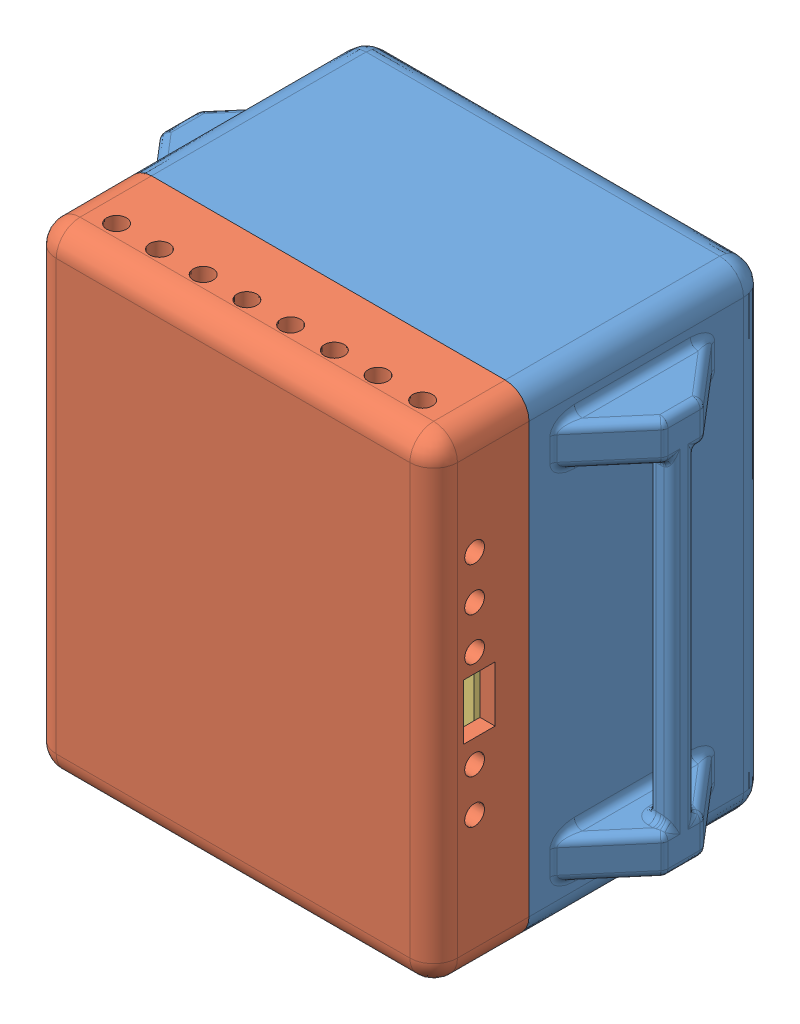
SolidWorks assembly CASE_BATTERIE_FUORI, configuration Default. Lengths in mm.
Overall size (50.5 60 40.1).
77 component instances, 44 part files, 13 mates.
Components (placement in the parent):
- Sotto-1: Sotto [Default] at (-26.2964 -32.0057 39.05) size (63.55 60 35)
- Sensiron-1: Sensiron [Default] at (-24.3964 -30.1057 49.95) x (1 0 0) z (0 -1 0) size (40 12 40) (hidden)
- BatterieSLDPRT-1: BatterieSLDPRT [Default] at (-24.3964 -25.9057 53.95) size (44 52 11) (hidden)
- AssiemePCB-1: AssiemePCB [Default] at (-5.3863 -1.9261 26.258) size (59.61 41 16.91) (hidden)
  - PCB(2).step-1: PCB(2).step [Default] at (-23.3102 -47.5911 44.908) size (45.7 41 1.78)
    - PCB Component.step-1: PCB Component.step [Default] at origin size (45.7 41 1.78)
      - Board.step-1: Board.step [Default] at origin size (41 41 1.58)
      - 2996TR.step-1: 2996TR.step [Default] at (40.14 34.65 0) x (1 0 0) z (0 0 -1) size (13.21 12.07 0.1)
      - 2996TR.step-2: 2996TR.step [Default] at (21.69 34.65 0) x (1 0 0) z (0 0 -1) size (13.21 12.07 0.1)
      - 2996TR.step-3: 2996TR.step [Default] at (20.86 59.95 0) x (-1 0 0) z (0 0 -1) size (13.21 12.07 0.1)
      - 2996TR.step-4: 2996TR.step [Default] at (39.96 59.63 0) x (-1 0 0) z (0 0 -1) size (13.21 12.07 0.1)
      - SCD41-D-R2.step-1: SCD41-D-R2.step [Default] at (41.35 59.4 1.584) size (12.1 12.1 0.1)
      - BSS138.step-1: BSS138.step [Default] at (39.94 37.09 1.584) size (3 3.14 0.1)
      - BSS138.step-2: BSS138.step [Default] at (47.24 35.01 1.584) x (0 1 0) z (0 0 1) size (3 3.14 0.1)
      - BSS138.step-3: BSS138.step [Default] at (26.44 55.43 1.584) x (0 1 0) z (0 0 1) size (3 3.14 0.1)
      - BSS138.step-4: BSS138.step [Default] at (32.54 55.75 1.584) x (0 1 0) z (0 0 1) size (3 3.14 0.1)
      - TSV912IDT.step-1: TSV912IDT.step [Default] at (28.16 33.68 1.584) x (0 -1 0) z (0 0 1) size (6.3 5.13 0.1)
      - SGP30.step-1: SGP30.step [Default] at (42.4 33.66 1.584) x (-1 0 0) z (0 0 1) size (2.88 2.88 0.1)
      - MICS-6814.step-1: MICS-6814.step [Default] at (20.41 33.71 1.584) x (0 1 0) z (0 0 1) size (6.34 7 0.1)
      - 317030213.step-1: 317030213.step [Default] at (18.77 47.25 1.584) x (0 1 0) z (0 0 1) size (11.45 16 0.1)
      - BME280.step-1: BME280.step [Default] at (43.18 50.09 1.584) size (2.95 2.77 0.1)
      - EG1213.step-1: EG1213.step [Default] at (48.7 47.1 1.584) x (0 1 0) z (0 0 1) size (11.2 9 0.1) (hidden)
      - MC78LC50NTRGTSOT23-5_ONS.step-1: MC78LC50NTRGTSOT23-5_ONS.step [Default] at (29.4 47.4 0) x (-1 0 0) z (0 0 -1) size (2.79 3.33 0.1)
      - MIC5219-3.3YMMMSOP-8LD-PL-1_MCH.step-1: MIC5219-3.3YMMMSOP-8LD-PL-1_MCH.step [Default] at (36 47.2 0) x (-1 0 0) z (0 0 -1) size (4.9 3.53 0.1)
      - S-1318D18-M5T1U4.step-1: S-1318D18-M5T1U4.step [Default] at (43.3 46.3 0) x (1 0 0) z (0 0 -1) size (4.2 3.6 0.1)
      - MMBT3904-215.step-1: MMBT3904-215.step [Default] at (18.6 39.2 1.584) x (0 -1 0) z (0 0 1) size (3.16 3.12 0.1)
      - ECS-.327-9-16-TR.step-1: ECS-.327-9-16-TR.step [Default] at (29.5 44.1 1.584) x (0 -1 0) z (0 0 1) size (1.6 1 0.1)
      - BG306-04-A-1-0400-X-X_REVD.step-1: BG306-04-A-1-0400-X-X_REVD.step [Default] at (18 61.2 1.584) x (0 -1 0) z (0 0 1) size (10.66 4 0.1)
      - STMICROELECTRONICS_LIS3DHSTMICROELECTRONICS_LIS3DH_0_0.step-1: STMICROELECTRONICS_LIS3DHSTMICROELECTRONICS_LIS3DH_0_0.step [Default] at (33.8 50.2 1.584) x (-1 0 0) z (0 0 1) size (3.43 3.15 0.1)
      - S5B-ZR-SM4A-TF_(LF)_(SN)CONN_S5B-ZR-SM4A-TF_JST.step-1: S5B-ZR-SM4A-TF_(LF)_(SN)CONN_S5B-ZR-SM4A-TF_JST.step [Default] at (24.1 59.8 1.584) size (12.9 6.25 0.1)
      - LTST-C170KRKT.step-1: LTST-C170KRKT.step [Default] at (48.7 55.3 1.584) x (0 -1 0) z (0 0 1) size (2 1.25 0.1)
      - MCS0402MC1002FE000.step-1: MCS0402MC1002FE000.step [Default] at (39.8 33.2 1.584) x (0 -1 0) z (0 0 1) size (1.06 0.56 0.1)
      - MCS0402MC1002FE000.step-2: MCS0402MC1002FE000.step [Default] at (39.8 39.9 1.584) size (1.06 0.56 0.1)
      - MCS0402MC1002FE000.step-3: MCS0402MC1002FE000.step [Default] at (44.8 34.1 1.584) x (0 -1 0) z (0 0 1) size (1.06 0.56 0.1)
      - MCS0402MC1002FE000.step-4: MCS0402MC1002FE000.step [Default] at (46.1 38.1 1.584) x (-1 0 0) z (0 0 1) size (1.06 0.56 0.1)
      - MCS0402MC1002FE000.step-5: MCS0402MC1002FE000.step [Default] at (29.2 57.1 1.584) x (0 -1 0) z (0 0 1) size (1.06 0.56 0.1)
      - MCS0402MC1002FE000.step-6: MCS0402MC1002FE000.step [Default] at (33 53.1 1.584) size (1.06 0.56 0.1)
      - MCS0402MC1002FE000.step-7: MCS0402MC1002FE000.step [Default] at (23.8 56.9 1.584) x (0 1 0) z (0 0 1) size (1.06 0.56 0.1)
      - MCS0402MC1002FE000.step-8: MCS0402MC1002FE000.step [Default] at (29.9 54.4 1.584) x (0 1 0) z (0 0 1) size (1.06 0.56 0.1)
      - ERJPA2F1300X.step-1: ERJPA2F1300X.step [Default] at (16.1 38.2 1.584) x (0 1 0) z (0 0 1) size (1 0.5 0.1)
      - ERJPA2J821X.step-1: ERJPA2J821X.step [Default] at (22.5 38.1 1.584) x (0 1 0) z (0 0 1) size (1 0.5 0.1)
      - ERA2AEB331X.step-1: ERA2AEB331X.step [Default] at (48.7 60.4 1.584) x (0 -1 0) z (0 0 1) size (1 0.5 0.1)
      - ERJPA2F5101X.step-1: ERJPA2F5101X.step [Default] at (21.4 40.3 1.584) x (0 -1 0) z (0 0 1) size (1 0.5 0.1)
      - ERJ-2GEJ106X.step-1: ERJ-2GEJ106X.step [Default] at (34.5 36.6 1.584) size (1.06 0.56 0.1)
      - ERJ-2GEJ106X.step-2: ERJ-2GEJ106X.step [Default] at (34.4 31.6 1.584) x (-1 0 0) z (0 0 1) size (1.06 0.56 0.1)
      - ERJ-2GEJ106X.step-3: ERJ-2GEJ106X.step [Default] at (32.5 45.7 0) x (0 1 0) z (0 0 -1) size (1.06 0.56 0.1)
      - ERJ-2GEJ106X.step-4: ERJ-2GEJ106X.step [Default] at (33.4 43 0) x (0 -1 0) z (0 0 -1) size (1.06 0.56 0.1)
      - ERJ-2GEJ515X.step-1: ERJ-2GEJ515X.step [Default] at (32.2 36.5 1.584) x (0 -1 0) z (0 0 1) size (1.06 0.56 0.1)
      - ERJ-2GEJ515X.step-2: ERJ-2GEJ515X.step [Default] at (32.1 32.5 1.584) x (0 -1 0) z (0 0 1) size (1.06 0.56 0.1)
      - C0402C104K9RACAUTO.step-1: C0402C104K9RACAUTO.step [Default] at (32 47.8 0) x (0 1 0) z (0 0 -1) size (1.06 0.96 0.1)
      - C0402C104K9RACAUTO.step-2: C0402C104K9RACAUTO.step [Default] at (29.4 45.1 0) x (-1 0 0) z (0 0 -1) size (1.06 0.96 0.1)
      - C0402C104K9RACAUTO.step-3: C0402C104K9RACAUTO.step [Default] at (43.2 31.1 1.584) size (1.06 0.96 0.1)
      - CL05A225MQ5NNNC.step-1: CL05A225MQ5NNNC.step [Default] at (39.7 44.8 0) x (1 0 0) z (0 0 -1) size (1.06 0.96 0.1)
      - CL05B471KB5NNNCCAP_CL05_SAM.step-1: CL05B471KB5NNNCCAP_CL05_SAM.step [Default] at (36.1 44.8 0) x (1 0 0) z (0 0 -1) size (1 0.5 0.1)
      - JMK105BJ105KV-F.step-1: JMK105BJ105KV-F.step [Default] at (40.6 46.7 0) x (0 1 0) z (0 0 -1) size (1.06 0.56 0.1)
      - JMK105BJ105KV-F.step-2: JMK105BJ105KV-F.step [Default] at (43.6 43.7 0) x (1 0 0) z (0 0 -1) size (1.06 0.56 0.1)
      - CL05B103KO5NNNC.step-1: CL05B103KO5NNNC.step [Default] at (34.4 38.5 1.584) x (-1 0 0) z (0 0 1) size (1.06 0.96 0.1)
      - CL05B103KO5NNNC.step-2: CL05B103KO5NNNC.step [Default] at (34.4 33.7 1.584) size (1.06 0.96 0.1)
      - CL05B103KO5NNNC.step-3: CL05B103KO5NNNC.step [Default] at (32.1 43 0) x (0 -1 0) z (0 0 -1) size (1.06 0.96 0.1)
      - CL05A106MP5NUNC.step-1: CL05A106MP5NUNC.step [Default] at (26.6 40.4 1.584) x (-1 0 0) z (0 0 1) size (1.06 0.96 0.1)
      - 04025A120FAT2A.step-1: 04025A120FAT2A.step [Default] at (31.6 43.3 1.584) x (-1 0 0) z (0 0 1) size (1.1 0.6 0.1)
      - 04025A120FAT2A.step-2: 04025A120FAT2A.step [Default] at (31.6 44.8 1.584) x (-1 0 0) z (0 0 1) size (1.1 0.6 0.1)
  - Micro.step-1: Micro.step [Default] at (-4.5401 -1.0595 46.492) x (0 1 0) z (1 0 0) size (10 2.2 16)
  - SCD41.step-1: SCD41.step [Default] at (18.0381 11.8123 47.292) size (10.1 10.1 6.31)
  - Programmatore.stp-1: Programmatore.stp [Default] at (-5.3139 13.6094 46.492) x (0 1 0) z (0 0 1) size (10.66 5 5.4)
    - Body.stp-1: Body.stp [Default] at (0 0 0.1) size (10.66 2.54 5.3)
    - Pins.stp-1: Pins.stp [Default] at origin size (8.44 5 0.1)
  - Battery_holder.step-2: Battery_holder.step [Default] at (16.5976 11.3464 44.908) x (-1 0 0) z (0 -1 0) size (17.78 5.99 12.06)
  - Battery_holder.step-4: Battery_holder.step [Default] at (-2.4492 11.6664 44.908) x (-1 0 0) z (0 -1 0) size (17.78 5.99 12.06)
  - Battery_holder.step-5: Battery_holder.step [Default] at (16.8288 -12.2486 44.908) x (1 0 0) z (0 1 0) size (17.78 5.99 12.06)
  - Battery_holder.step-6: Battery_holder.step [Default] at (-1.6212 -12.2486 44.908) x (1 0 0) z (0 1 0) size (17.78 5.99 12.06)
  - EG1213--3DModel-STEP-520916.step-1: EG1213--3DModel-STEP-520916.step [Default] at (25.3922 -0.5224 47.292) x (1 0 0) z (0 -1 0) size (8.8 7.9 10)
  - SGP30.step-1: SGP30.step [Default] at (19.3022 -14.1458 46.492) x (-1 0 0) z (0 1 0) size (2.88 2.88 0.1)
  - SGP30.step-3: SGP30.step [Default] at (44.7999 -15.0699 54.1823) x (1 0 0) z (0 -1 0) size (2.88 2.88 0.1) (hidden)
  - SGP30.step-5: SGP30.step [Default] at (45.0699 -18.2823 49.3168) x (1 0 0) z (0 -1 0) size (2.88 2.88 0.1) (hidden)
- Sopra-1: Sopra [Default] at (24.2036 -32.0057 81.05) x (-1 0 0) z (0 -1 0) size (50.5 12 60)
- Fermo_SPS-1: Fermo_SPS [Default] at (-5.834 11.9643 53.95) x (1 0 0) z (0 1 0) size (8 13 48.73)
Mates (geometry in assembly coordinates):
- Coincidente1: coincident anti-aligned: plane of Sotto-1 through (-26.2964 -32.0057 40.95) normal (0 0 1); plane of Sensiron-1 through (-24.3964 -30.1057 40.95) normal (0 0 -1)
- Coincidente2: coincident anti-aligned: plane of Sotto-1 through (-24.3964 27.9943 70.95) normal (1 0 0); plane of Sensiron-1 through (-24.3964 -30.1057 40.95) normal (-1 0 0)
- Coincidente3: coincident anti-aligned: plane of Sotto-1 through (-24.3964 -30.1057 70.95) normal (0 1 0); plane of Sensiron-1 through (-24.3964 -30.1057 40.95) normal (0 -1 0)
- Coincidente5: coincident anti-aligned: plane of Sotto-1 through (-24.3964 27.9943 70.95) normal (1 0 0); plane of BatterieSLDPRT-1 through (-24.3964 -25.9057 64.95) normal (-1 0 0)
- Coincidente6: coincident anti-aligned: plane of Sotto-1 through (-24.3964 26.0943 70.95) normal (0 -1 0); plane of BatterieSLDPRT-1 through (-24.3964 26.0943 64.95) normal (0 1 0)
- Coincidente7: coincident anti-aligned: plane of Sotto-1 through (-26.2964 -32.0057 53.95) normal (0 0 1); plane of BatterieSLDPRT-1 through (-24.3964 -25.9057 53.95) normal (0 0 -1)
- Coincidente8: coincident: line of AssiemePCB-1/PCB(2).step-1/PCB Component.step-1/Board.step-1 through (22.3036 -22.5172 71.166) axis (0 1 0); plane of Sopra-1 through (22.3036 27.9943 69.05) normal (-1 0 0)
- Coincidente9: coincident anti-aligned: plane of AssiemePCB-1/PCB(2).step-1/PCB Component.step-1/Board.step-1 through (1.8036 -2.0172 72.75) normal (0 0 1); plane of Sopra-1 through (24.2036 -32.0057 72.75) normal (0 0 -1)
- Coincidente11: coincident aligned: plane of Sotto-1 through (24.2036 -32.0057 40.95) normal (1 0 0); plane of Sopra-1 through (24.2036 -32.0057 79.05) normal (1 0 0)
- Coincidente12: coincident aligned: plane of Sotto-1 through (-26.2964 -32.0057 40.95) normal (0 -1 0); plane of Sopra-1 through (24.2036 -32.0057 79.05) normal (0 -1 0)
- Coincidente13: coincident anti-aligned: plane of Sopra-1 through (24.2036 -32.0057 69.05) normal (0 0 -1); plane of Sotto-1 through (-26.2964 -32.0057 69.05) normal (0 0 1)
- Coincidente14: coincident anti-aligned: plane of Sotto-1 through (-24.3964 -30.1057 70.95) normal (0 1 0); plane of Fermo_SPS-1 through (-5.834 -30.1057 52.95) normal (0 -1 0)
- Coincidente15: coincident anti-aligned: plane of Sensiron-1 through (-24.3964 -30.1057 52.95) normal (0 0 1); plane of Fermo_SPS-1 through (-5.834 11.9643 52.95) normal (0 0 -1)
